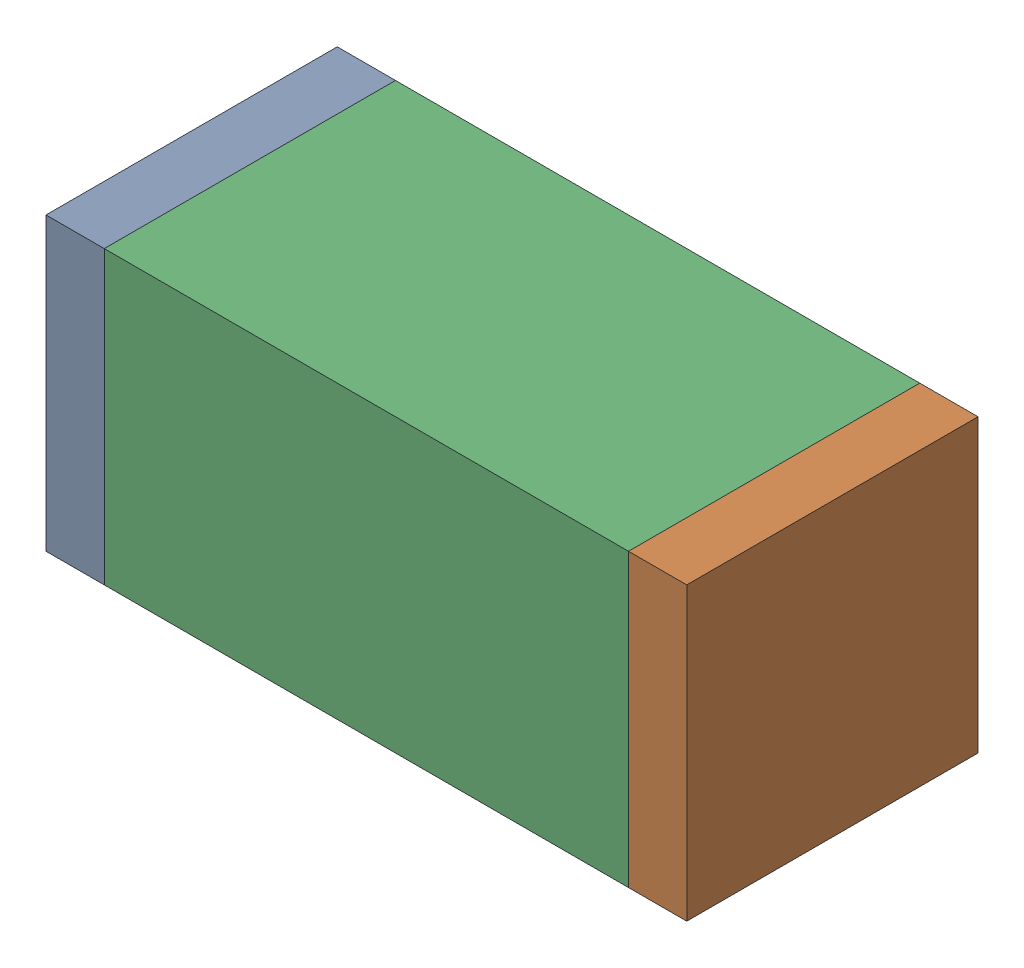
SolidWorks assembly C61, configuration Default. Lengths in mm.
Overall size (1.1 0.5 0.5).
6 component instances, 2 part files, 0 mates.
Components (placement in the parent):
- 810156080-1: 810156080 [Default] at (119.9 52.6 0) size (0.1 0.5 0.5)
  - Extruded_5-1: Extruded_5 [Default] at origin size (0.1 0.5 0.5)
- 810156080-2: 810156080 [Default] at (120.9 52.6 0) size (0.1 0.5 0.5)
  - Extruded_5-1: Extruded_5 [Default] at origin size (0.1 0.5 0.5)
- 836749680-1: 836749680 [Default] at (120.4 52.6 0) size (0.9 0.5 0.5)
  - Extruded_4-1: Extruded_4 [Default] at origin size (0.9 0.5 0.5)
